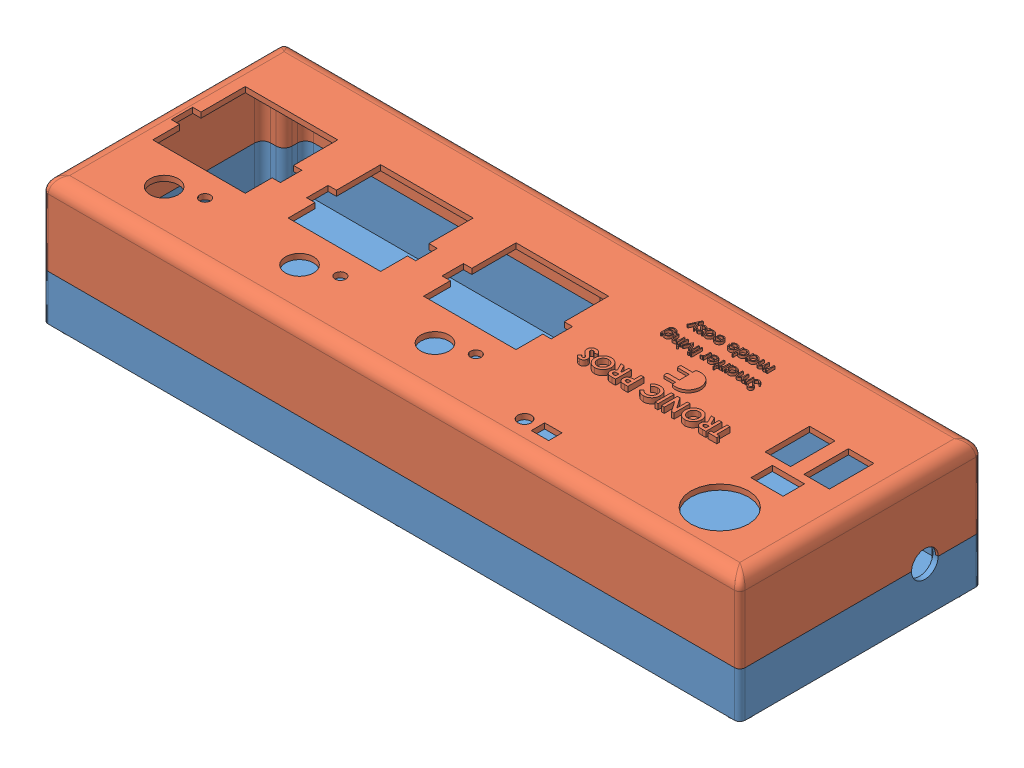
SolidWorks assembly Assem2, configuration Default. Lengths in mm.
Overall size (260 51 90).
2 component instances, 2 part files, 3 mates.
Components (placement in the parent):
- solid_lower-1: solid_lower [Default] at (80.6786 92.6211 237.4668) size (260 26 90)
- SW_upper-1: SW_upper [Default] at (80.6786 139.6211 237.4668) x (1 0 0) z (0 0 -1) size (260 32 90)
Mates (geometry in assembly coordinates):
- Coincident1: coincident anti-aligned: plane of solid_lower-1 through (80.6786 112.6211 237.4668) normal (0 1 0); plane of SW_upper-1 through (80.6786 112.6211 237.4668) normal (0 -1 0)
- Coincident2: coincident anti-aligned: plane of solid_lower-1 through (80.6786 109.6211 237.4668) normal (0 1 0); plane of SW_upper-1 through (80.6786 109.6211 237.4668) normal (0 -1 0)
- Concentric1: concentric anti-aligned: circle of solid_lower-1; circle of SW_upper-1
